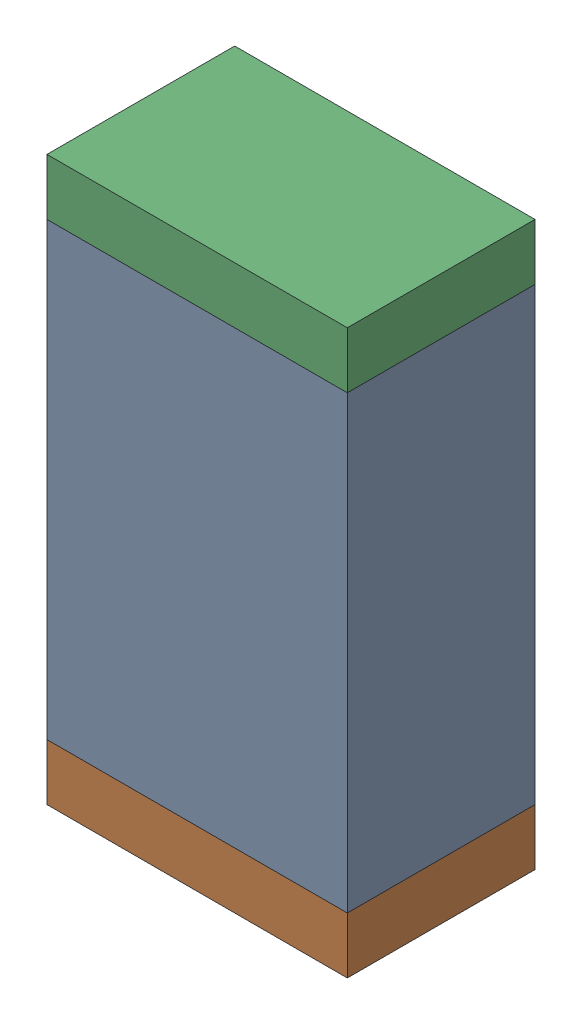
SolidWorks assembly C81, configuration Default. Lengths in mm.
Overall size (0.8 1.5 0.5).
6 component instances, 2 part files, 0 mates.
Components (placement in the parent):
- 810156976-1: 810156976 [Default] at (106.6 62.1 0) size (0.8 1.2 0.5)
  - Extruded_6-1: Extruded_6 [Default] at origin size (0.8 1.2 0.5)
- 810156592-1: 810156592 [Default] at (106.6 61.425 0) size (0.8 0.15 0.5)
  - Extruded_7-1: Extruded_7 [Default] at origin size (0.8 0.15 0.5)
- 810156592-2: 810156592 [Default] at (106.6 62.775 0) size (0.8 0.15 0.5)
  - Extruded_7-1: Extruded_7 [Default] at origin size (0.8 0.15 0.5)
